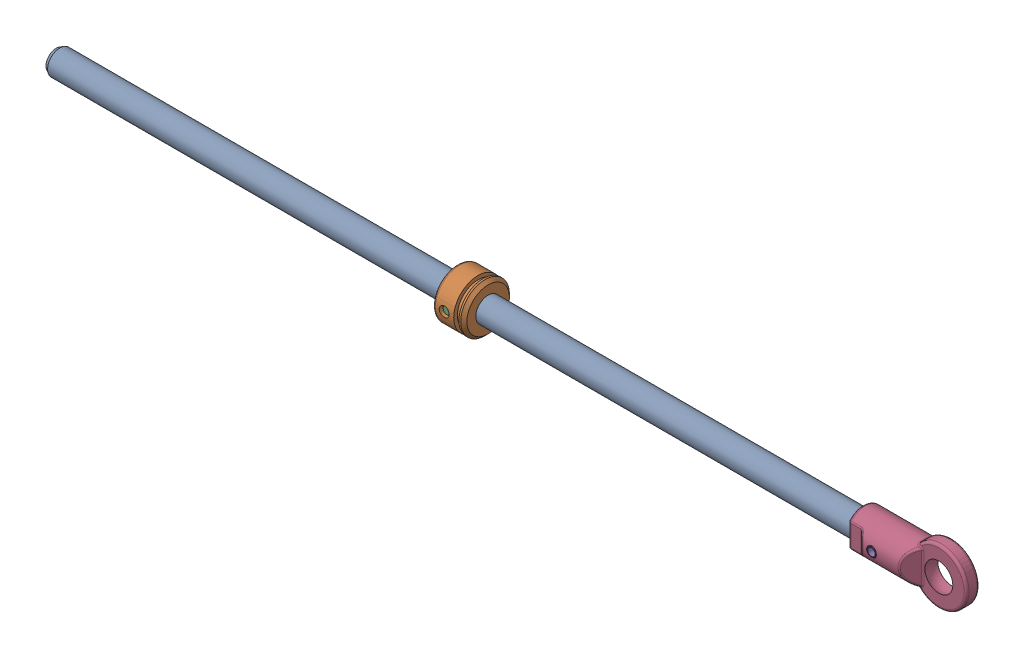
SolidWorks assembly SE_Tige piston, configuration Défaut. Lengths in mm.
Overall size (745 45 39.5).
5 component instances, 5 part files, 8 mates.
Components (placement in the parent):
- tige speciale-1: tige speciale [Défaut] at origin size (688 20 20)
- Piston VHM40DTP-1: Piston VHM40DTP [Défaut] at (208 0 0) size (25 39.5 39.5)
- axe de piston-1: axe de piston [Défaut] at (193 0 -17.5) size (8 8 35)
- EmboutRotule-1: EmboutRotule [Default] at (580.5 0 0) x (0 1 0) z (-1 0 0) size (45 30 89.5)
- GoupilleFendue-1: GoupilleFendue [Default] at (535.5 0 0) size (8 7.97 30)
Mates (geometry in assembly coordinates):
- Concentrique1: concentric aligned: cylinder of tige speciale-1 through (193 0 -15) axis (0 0 1) radius 4; cylinder of Piston VHM40DTP-1 through (193 0 -19.75) axis (0 0 1) radius 4
- Concentrique2: concentric aligned: cylinder of tige speciale-1 through (-98 0 0) axis (-1 0 0) radius 10; cylinder of Piston VHM40DTP-1 through (116 0 0) axis (-1 0 0) radius 10
- Concentrique3: concentric anti-aligned: cylinder of Piston VHM40DTP-1 through (193 0 -19.75) axis (0 0 1) radius 4; cylinder of axe de piston-1 through (193 0 17.5) axis (0 0 -1) radius 4
- A distance1: distance = 17.5 mm aligned: plane of axe de piston-1 through (193 0 17.5) normal (0 0 1); plane of assembly
- Coaxial1: concentric anti-aligned: cylinder of tige speciale-1 through (535.5 0 -15) axis (0 0 1) radius 4; cylinder of EmboutRotule-1 through (535.5 0 15) axis (0 0 -1) radius 4
- Coaxial2: concentric aligned: cylinder of tige speciale-1 through (-98 0 0) axis (-1 0 0) radius 9; cylinder of EmboutRotule-1 through (513.5 0 0) axis (-1 0 0) radius 9
- Coaxial3: concentric aligned: cylinder of EmboutRotule-1 through (535.5 0 15) axis (0 0 -1) radius 4; cylinder of GoupilleFendue-1 through (535.5 0 15) axis (0 0 -1) radius 4
- Coïncidente1: coincident anti-aligned: plane of EmboutRotule-1; plane of GoupilleFendue-1
